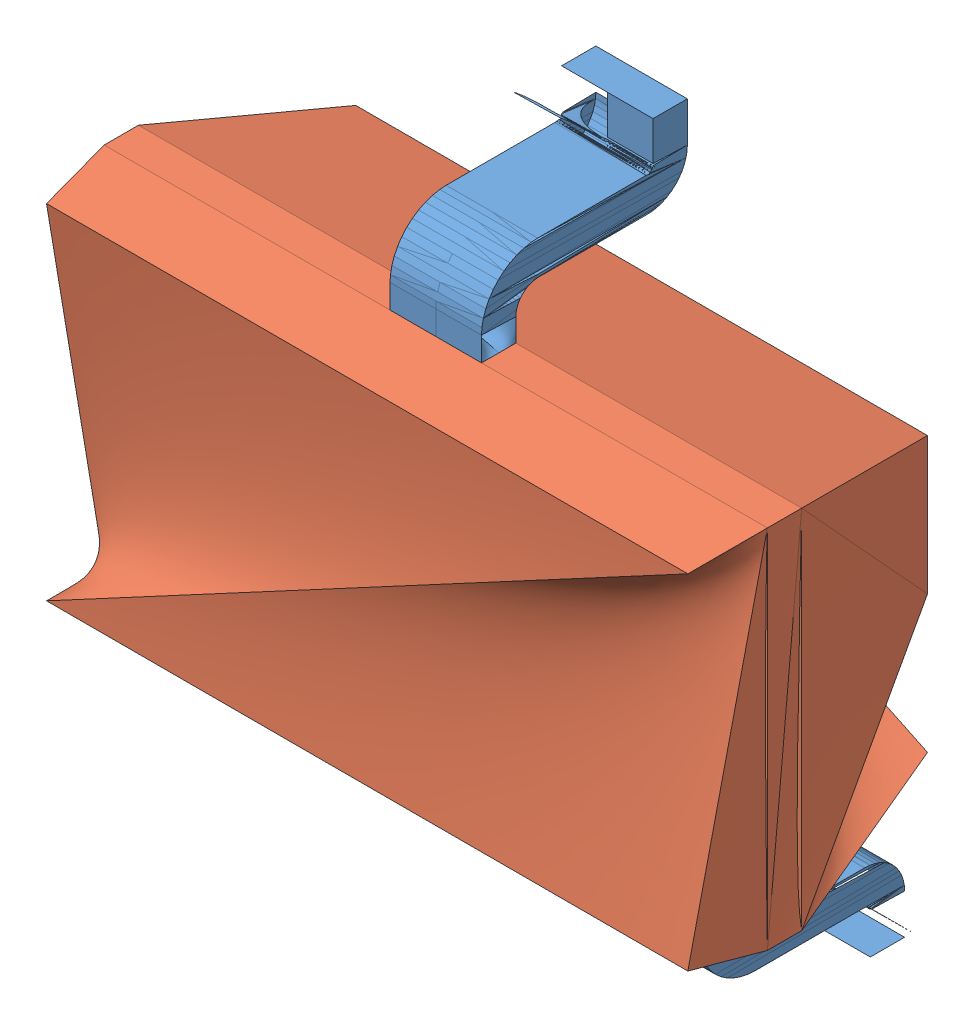
SolidWorks assembly SOT23, configuration Default. Lengths in mm.
Overall size (2.88 2.68 1.19).
4 component instances, 2 part files, 0 mates.
Components (placement in the parent):
- Groupe_1-1: Groupe_1 [Default] at (-0.9426 -1.0666 -0.1488) size (0.66 0.55 0.89)
- Groupe_1-2: Groupe_1 [Default] at (0.9426 -1.0666 -0.1488) size (0.66 0.55 0.89)
- Groupe_1-3: Groupe_1 [Default] at (0 1.0666 -0.1488) x (-1 0 0) z (0 0 1) size (0.66 0.55 0.89)
- SOT23-1: SOT23 [Default] at origin size (2.88 1.59 1.19)
